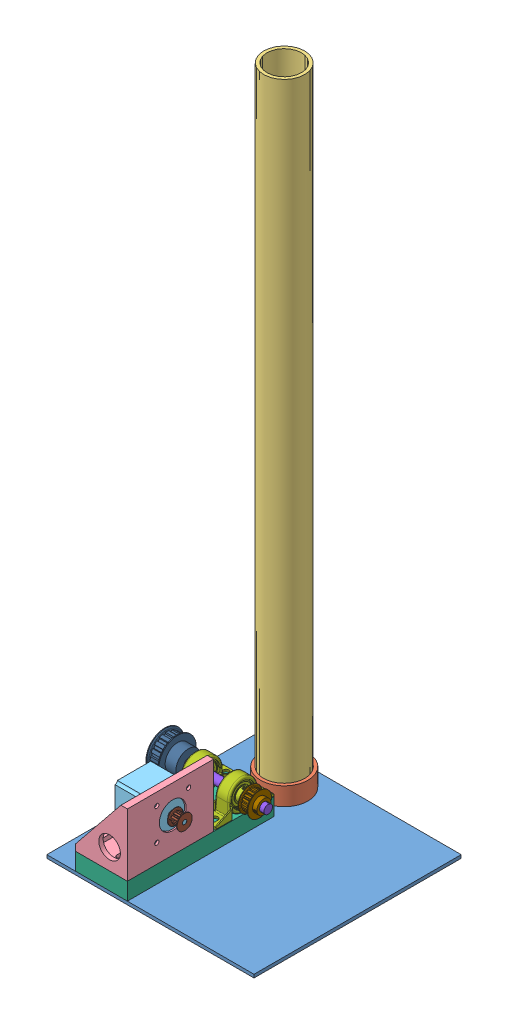
SolidWorks assembly Base Plate, configuration Default. Lengths in mm.
Overall size (304.8 943.9 304.8).
12 component instances, 11 part files, 26 mates.
Components (placement in the parent):
- Base Plate-1: Base Plate [Default] at origin size (304.8 4.76 304.8)
- 1608T194_STANDARD-WALL BLACK ABS PIPE   PIPE FITTING-1: 1608T194_STANDARD-WALL BLACK ABS PIPE   PIPE FITTING [1608T194] at (88.9 4.7625 -260.35) x (0 -1 0) z (0 0 1) size (47.39 69.85 69.85)
- 36_inch_abs_pipe-2: 36_inch_abs_pipe [Default] at (88.9 13.4572 -260.35) x (0.845689 0 -0.533676) z (0.533676 0 0.845689) size (60.32 914.4 60.32)
- stepper bracket-1: stepper bracket [Default] at (118.5564 30.1625 0) x (0 0 -1) z (1 0 0) size (127 92.08 76.2)
- stepper motor-1: stepper motor [Default] at (109.9204 52.8955 -94.742) x (0 1 0) z (1 0 0) size (56.13 56.13 74.42)
- Spacer Block-1: Spacer Block [Default] at (118.5564 4.7625 0) x (-1 0 0) z (0 0 -1) size (76.2 25.4 215.9)
- 5913K610_LOW-PROFILE MOUNTED BALL BEARING-1: 5913K610_LOW-PROFILE MOUNTED BALL BEARING [5913K61] at (54.6596 52.3875 -173.0375) x (0 0 1) z (-1 0 0) size (85.72 43.66 28.58)
- 5913K610_LOW-PROFILE MOUNTED BALL BEARING-2: 5913K610_LOW-PROFILE MOUNTED BALL BEARING [5913K61] at (106.2533 52.3875 -173.0375) x (0 0 -1) z (1 0 0) size (85.72 43.66 28.58)
- 1_2 inch shaft-1: 1_2 inch shaft [Default] at (152.6877 52.3875 -173.0375) x (0 0 1) z (-1 0 0) size (12.7 12.7 152.4)
- 6495K749_TIMING BELT PULLEY-1: 6495K749_TIMING BELT PULLEY [6495K749] at (136.0126 52.3875 -173.0375) x (0 -0.188319 0.982108) z (1 0 0) size (34.92 34.92 20.62)
- 6495K150_TIMING BELT PULLEY-1: 6495K150_TIMING BELT PULLEY [6495K15] at (17.7502 52.3875 -173.0375) x (0 -0.255878 -0.966709) z (1 0 0) size (54.76 54.76 34.92)
- 6495K744_TIMING BELT PULLEY-1: 6495K744_TIMING BELT PULLEY [6495K744] at (125.77 80.9625 -66.675) x (0 0.924225 0.381849) z (-1 0 0) size (22.23 22.23 20.62)
Mates (geometry in assembly coordinates):
- Coincident1: coincident anti-aligned: plane of Base Plate-1 through (0 4.7625 0) normal (0 1 0); plane of 1608T194_STANDARD-WALL BLACK ABS PIPE   PIPE FITTING-1 through (62.6491 4.7625 -260.35) normal (0 -1 0)
- Concentric1: concentric anti-aligned: cylinder of Base Plate-1 through (88.9 0 -260.35) axis (0 1 0) radius 30.1625; cylinder of 1608T194_STANDARD-WALL BLACK ABS PIPE   PIPE FITTING-1 through (88.9 -14.7066 -260.35) axis (0 -1 0) radius 26.2509
- Concentric3: concentric aligned: cone of 1608T194_STANDARD-WALL BLACK ABS PIPE   PIPE FITTING-1 through (88.9 12.2936 -260.35) axis (0 -1 0); cylinder of 36_inch_abs_pipe-2 through (88.9 927.8572 -260.35) axis (0 -1 0) radius 30.1625
- Lock1: lock: unknown of 1608T194_STANDARD-WALL BLACK ABS PIPE   PIPE FITTING-1; unknown of 36_inch_abs_pipe-2
- Concentric5: concentric aligned: cylinder of stepper bracket-1 through (118.5564 80.9625 -66.675) axis (-1 0 0) radius 19.685; cylinder of stepper motor-1 through (117.0324 80.9625 -66.675) axis (-1 0 0) radius 19.05
- Coincident3: coincident anti-aligned: plane of stepper bracket-1 through (118.5564 30.1625 0) normal (0 -1 0); plane of Spacer Block-1 through (118.5564 30.1625 -215.9) normal (0 1 0)
- Coincident4: coincident aligned: plane of stepper bracket-1 through (118.5564 39.6875 0) normal (1 0 0); plane of Spacer Block-1 through (118.5564 4.7625 -215.9) normal (1 0 0)
- Coincident6: coincident aligned: plane of stepper bracket-1 through (118.5564 39.6875 0) normal (0 0 1); plane of Spacer Block-1 through (118.5564 4.7625 0) normal (0 0 1)
- Coincident7: coincident anti-aligned: plane of Spacer Block-1 through (118.5564 30.1625 -215.9) normal (0 1 0); plane of 5913K610_LOW-PROFILE MOUNTED BALL BEARING-2 through (118.5564 30.1625 -193.1353) normal (0 -1 0)
- Coincident8: coincident anti-aligned: plane of Spacer Block-1 through (118.5564 30.1625 -215.9) normal (0 1 0); plane of 5913K610_LOW-PROFILE MOUNTED BALL BEARING-1 through (42.3564 30.1625 -152.9398) normal (0 -1 0)
- Coincident9: coincident aligned: plane of 5913K610_LOW-PROFILE MOUNTED BALL BEARING-2 through (118.5564 32.004 -193.1353) normal (1 0 0); plane of Spacer Block-1 through (118.5564 4.7625 -215.9) normal (1 0 0)
- Coincident10: coincident aligned: plane of 5913K610_LOW-PROFILE MOUNTED BALL BEARING-2 through (118.5564 31.75 -215.9) normal (0 0 -1); plane of Spacer Block-1 through (118.5564 4.7625 -215.9) normal (0 0 -1)
- Coincident11: coincident aligned: plane of 5913K610_LOW-PROFILE MOUNTED BALL BEARING-1 through (42.3564 32.004 -152.9398) normal (-1 0 0); plane of Spacer Block-1 through (42.3564 4.7625 -215.9) normal (-1 0 0)
- Coincident12: coincident aligned: plane of Spacer Block-1 through (118.5564 4.7625 -215.9) normal (0 0 -1); plane of 5913K610_LOW-PROFILE MOUNTED BALL BEARING-1 through (42.3564 30.1625 -215.9) normal (0 0 -1)
- Coincident13: coincident anti-aligned: plane of Base Plate-1 through (0 4.7625 0) normal (0 1 0); plane of Spacer Block-1 through (118.5564 4.7625 -215.9) normal (0 -1 0)
- Coincident14: coincident aligned: plane of Base Plate-1 through (0 4.7625 0) normal (0 0 1); plane of Spacer Block-1 through (118.5564 4.7625 0) normal (0 0 1)
- Parallel2: parallel aligned: plane of stepper bracket-1 through (118.5564 122.2375 0) normal (0 1 0); plane of stepper motor-1 through (115.3814 109.0295 -94.742) normal (0 1 0)
- Concentric6: concentric anti-aligned: cylinder of 5913K610_LOW-PROFILE MOUNTED BALL BEARING-1 through (60.2158 52.3875 -173.0375) axis (-1 0 0) radius 6.35; cylinder of 1_2 inch shaft-1 through (0.2877 52.3875 -173.0375) axis (1 0 0) radius 6.35
- Distance1: distance = 38.1 mm aligned: plane of 1_2 inch shaft-1 through (0.2877 52.3875 -173.0375) normal (-1 0 0); plane of 5913K610_LOW-PROFILE MOUNTED BALL BEARING-1 through (38.3877 52.3875 -173.0375) normal (-1 0 0)
- Concentric8: concentric aligned: cylinder of 1_2 inch shaft-1 through (0.2877 52.3875 -173.0375) axis (1 0 0) radius 6.35; cylinder of 6495K749_TIMING BELT PULLEY-1 through (146.325 52.3875 -173.0375) axis (1 0 0) radius 6.35
- Distance2: distance = 3.175 mm anti-aligned: plane of 5913K610_LOW-PROFILE MOUNTED BALL BEARING-2 through (122.5252 52.3875 -173.0375) normal (1 0 0); plane of 6495K749_TIMING BELT PULLEY-1 through (125.7002 69.5376 -169.749) normal (-1 0 0)
- Concentric11: concentric aligned: cylinder of stepper motor-1 through (136.0824 80.9625 -66.675) axis (-1 0 0) radius 3.175; cylinder of 6495K744_TIMING BELT PULLEY-1 through (115.4576 80.9625 -66.675) axis (-1 0 0) radius 3.175
- Concentric12: concentric aligned: cylinder of 1_2 inch shaft-1 through (0.2877 52.3875 -173.0375) axis (1 0 0) radius 6.35; cylinder of 6495K150_TIMING BELT PULLEY-1 through (35.2127 52.3875 -173.0375) axis (1 0 0) radius 6.35
- Coincident19: coincident aligned: plane of 1_2 inch shaft-1 through (0.2877 52.3875 -173.0375) normal (-1 0 0); plane of 6495K150_TIMING BELT PULLEY-1 through (0.2877 25.9178 -166.0312) normal (-1 0 0)
- Coincident20: coincident aligned: plane of stepper motor-1 through (136.0824 80.9625 -66.675) normal (1 0 0); plane of 6495K744_TIMING BELT PULLEY-1 through (136.0824 76.7192 -56.4046) normal (1 0 0)
- Coincident21: coincident anti-aligned: plane of stepper bracket-1 through (115.3814 30.1625 0) normal (-1 0 0); plane of stepper motor-1 through (115.3814 52.8955 -94.742) normal (1 0 0)
